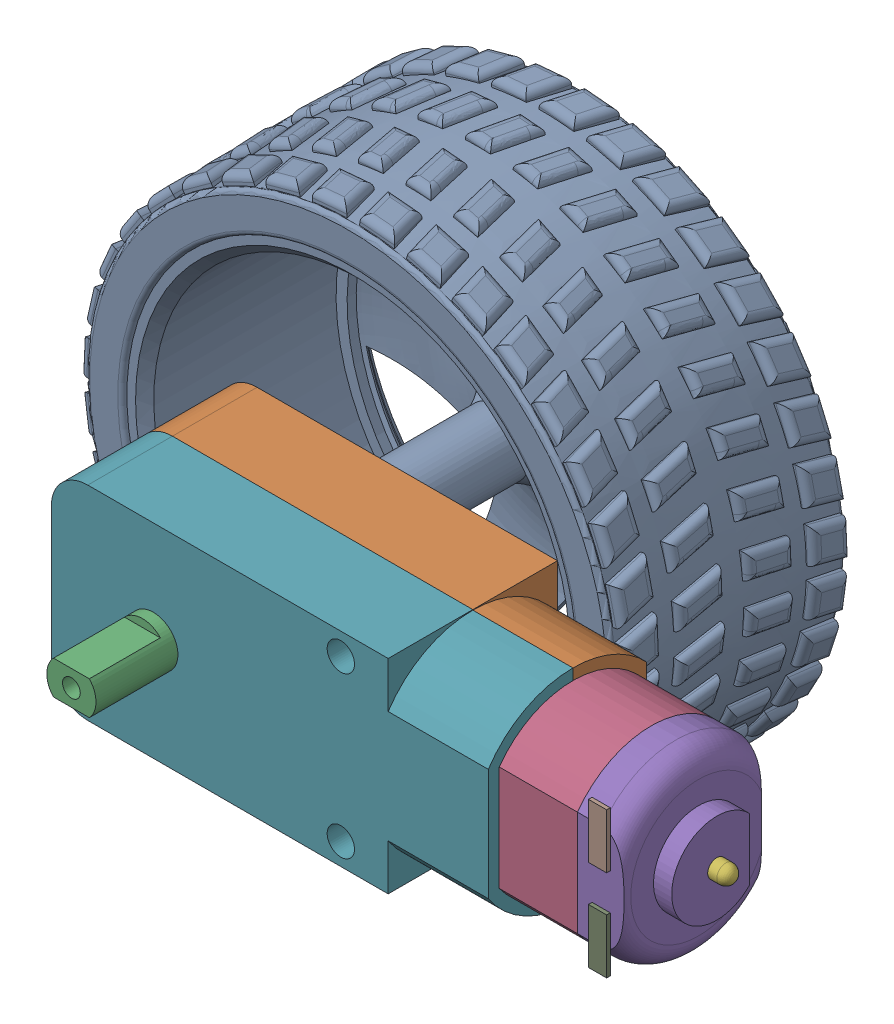
SolidWorks assembly wheel+motor right, configuration Default. Lengths in mm.
Overall size (90.64 72.19 56.74).
2 component instances, 2 part files, 7 mates.
Components (placement in the parent):
- wheel1-1: wheel1 [Default] at (0 0 -25) x (-0.97472 0.223429 0) z (0 0 1) size (60.22 60.26 27.94)
- 3777 TT Motor-1: 3777 TT Motor [Default] x (0 -1 0) z (-1 0 0) size (22.4 36.6 70.6)
Mates (geometry in assembly coordinates):
- Parallel1: parallel anti-aligned: plane of 3777 TT Motor-1 through (38.8018 0 0) normal (0 -1 0)
- Parallel2: parallel anti-aligned: plane of 3777 TT Motor-1 through (38.8018 0 0) normal (-1 0 0)
- Concentric1: concentric anti-aligned: cylinder of wheel1-1 through (38.8018 0 -37.5) axis (0 0 -1) radius 2.5; cylinder of 3777 TT Motor-1 through (38.8018 0 0) axis (0 0 1) radius 2.7
- Coincident1: coincident aligned: plane of 3777 TT Motor-1 through (38.8018 0 0) normal (0 0 1)
- Coincident2: coincident anti-aligned: plane of wheel1-1 through (38.0198 -3.4115 -10.5) normal (0 0 1); plane of 3777 TT Motor-1 through (38.8018 0 -10.5) normal (0 0 -1)
- Coincident3: coincident anti-aligned: plane of 3777 TT Motor-1 through (38.8018 0 0) normal (0 -1 0)
- Coincident4: coincident anti-aligned: plane of 3777 TT Motor-1 through (38.8018 0 0) normal (-1 0 0)
